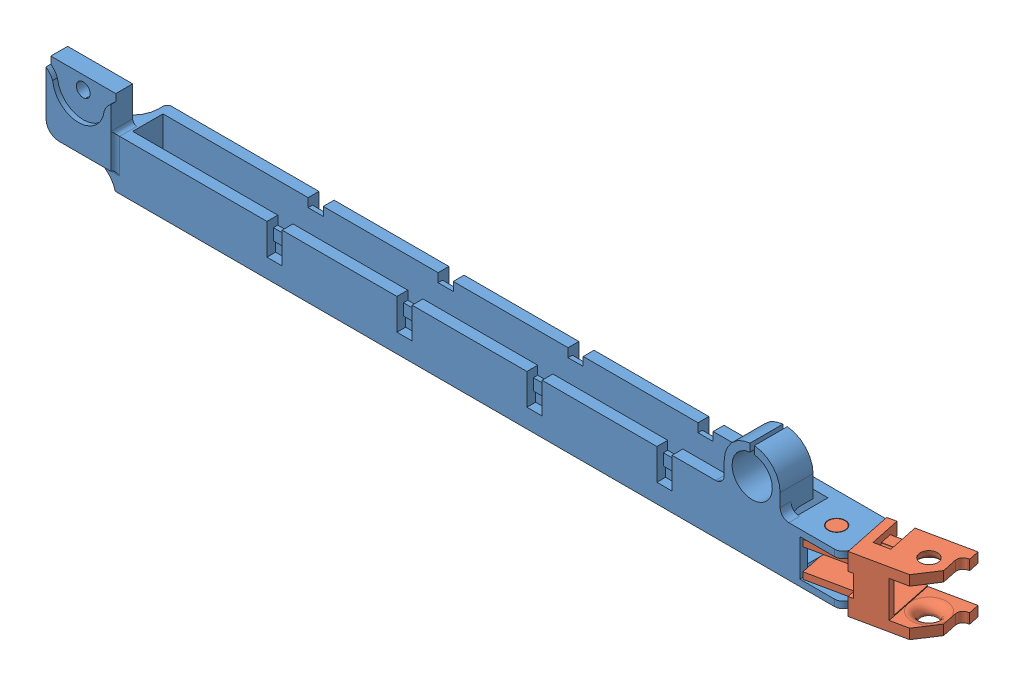
SolidWorks assembly EnsamblajeBandejaY, configuration Predeterminado. Lengths in mm.
Overall size (201.07 23.93 16.97).
2 component instances, 2 part files, 2 mates.
Components (placement in the parent):
- Soporte Base V2-1: Soporte Base V2 [Predeterminado] at (-79.3559 -13.9434 186.3466) size (183.03 23.35 13.31)
- Eslabon 5 Bloqueado-2: Eslabon 5 Bloqueado [Predeterminado] at (104.8555 -4.4434 182.4679) x (-0.978793 0 0.204852) z (0 -1 0) size (27.9 11.5 13)
Mates (geometry in assembly coordinates):
- Concéntrica2: concentric aligned: circle of Soporte Base V2-1; circle of Eslabon 5 Bloqueado-2
- Coincidente2: coincident anti-aligned: plane of Soporte Base V2-1 through (77.3441 -12.4434 174.3466) normal (0 1 0); plane of Eslabon 5 Bloqueado-2 through (88.8875 -12.4434 184.2773) normal (0 -1 0)
